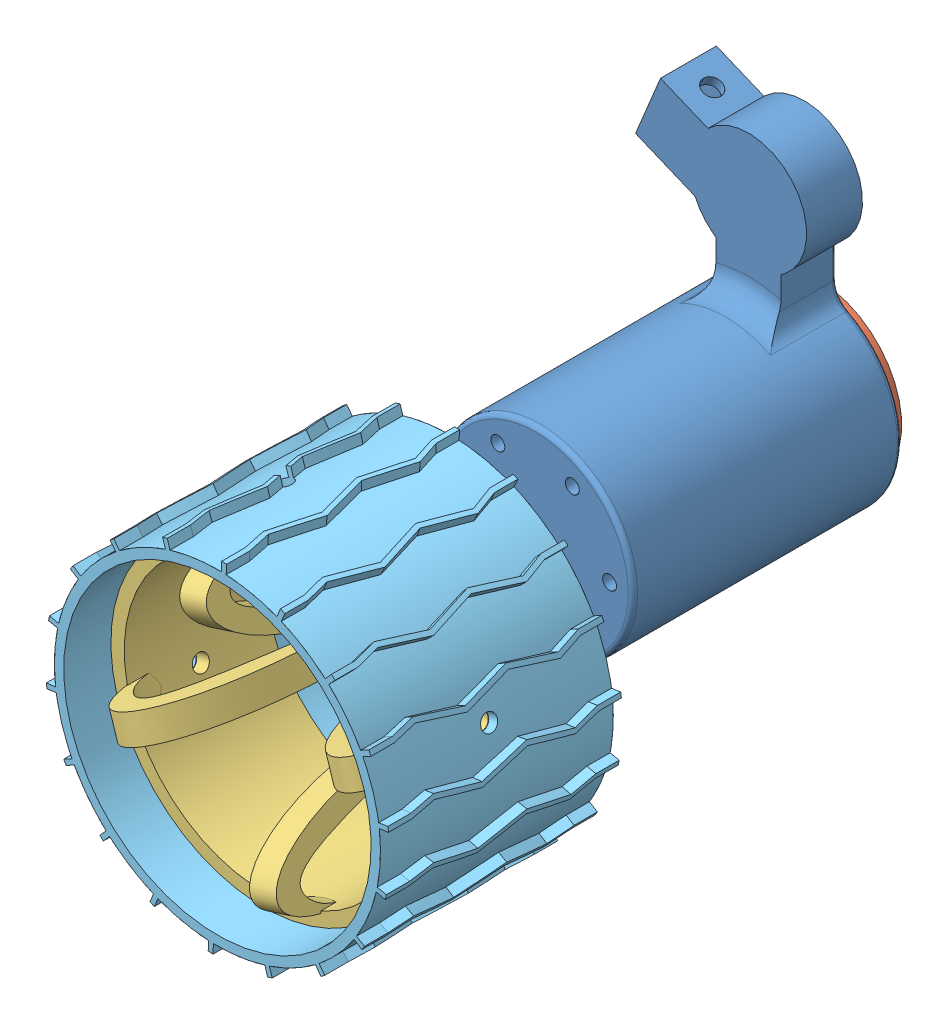
SolidWorks assembly Middle Wheel Flipped, configuration Default. Lengths in mm.
Overall size (92.57 106.34 128.8).
6 component instances, 5 part files, 2 mates.
Components (placement in the parent):
- A_H_Motor_F-1: A_H_Motor_F [Default] at (-18.4554 19.9771 -15.6006) size (45.23 74.39 57.8)
- Motor x Wheel Assembly-1: Motor x Wheel Assembly [Default] at (41.9016 -23.3264 54.9872) x (1 0 0) z (0 0 -1) size (92.57 92.9 128.8)
  - motor-1: motor [Default] at (-60.357 -3.1473 15.5878) size (37 37 78.8)
  - wheel inner-1: wheel inner [Default] at (-60.357 3.3527 -15.4122) x (0.952401 -0.304848 0) z (0.304848 0.952401 0) size (65.75 39.75 65.75)
  - wheel x motor connector test 2-1: wheel x motor connector test 2 [Default] at (-60.357 3.3527 9.5878) x (0.889009 0.457889 0) z (0 0 -1) size (25 25 25)
  - wheel outer-1: wheel outer [Default] at (-60.357 3.3527 -55.4122) x (-0.304848 -0.952401 0) z (0 0 1) size (74.01 73.51 50)
Mates (geometry in assembly coordinates):
- Coincident1: coincident anti-aligned: circle of A_H_Motor_F-1; circle of Motor x Wheel Assembly-1/motor-1
- Coincident2: coincident aligned: cylinder of A_H_Motor_F-1 through (-34.4554 -20.1791 -15.6006) axis (0 0 1) radius 1.5; circle of Motor x Wheel Assembly-1/motor-1
